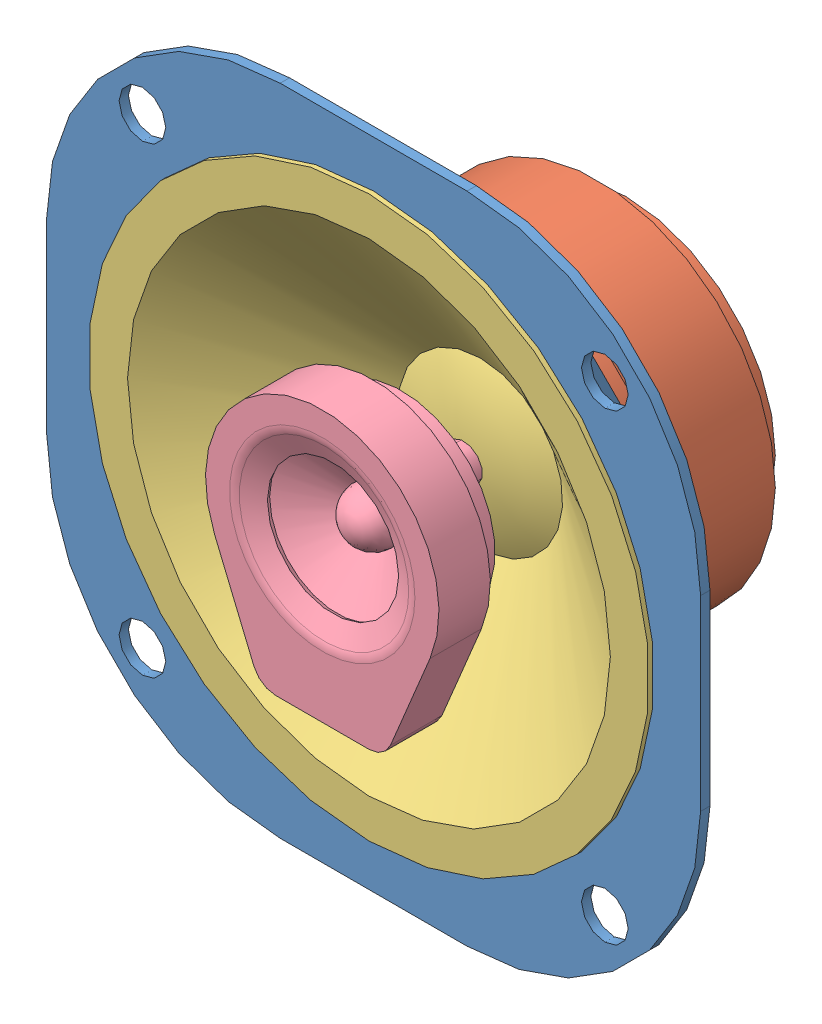
SolidWorks assembly speaker, configuration Dual Speaker. Lengths in mm.
Overall size (70 70 32.5).
4 component instances, 4 part files, 4 mates.
Components (placement in the parent):
- speaker_frame-1: speaker_frame [Square Cutout Mountable] at origin size (70 70 12)
- magnet-1: magnet [Default] at (0 0 -12) size (38 38 15)
- membrane-1: membrane [Default] at origin size (60 60 12.5)
- second_speaker-1: second_speaker [Default] at origin size (25 29 17.5)
Mates (geometry in assembly coordinates):
- Coincident2: coincident anti-aligned: plane of speaker_frame-1 through (0 18 -12) normal (0 0 -1); plane of magnet-1 through (0 0 -12) normal (0 0 1)
- Concentric1: concentric aligned: cylinder of speaker_frame-1 through (0 0 0) axis (0 0 1) radius 15; cylinder of magnet-1 through (0 0 -12) axis (0 0 1) radius 19
- Coincident4: coincident anti-aligned: plane of speaker_frame-1 through (-10 10 0) normal (0 0 1); plane of ? through (0 30 0) normal (0 0 -1)
- Concentric2: concentric anti-aligned: circle of speaker_frame-1; cylinder of ? through (0 0 -12) axis (0 0 -1) radius 30
